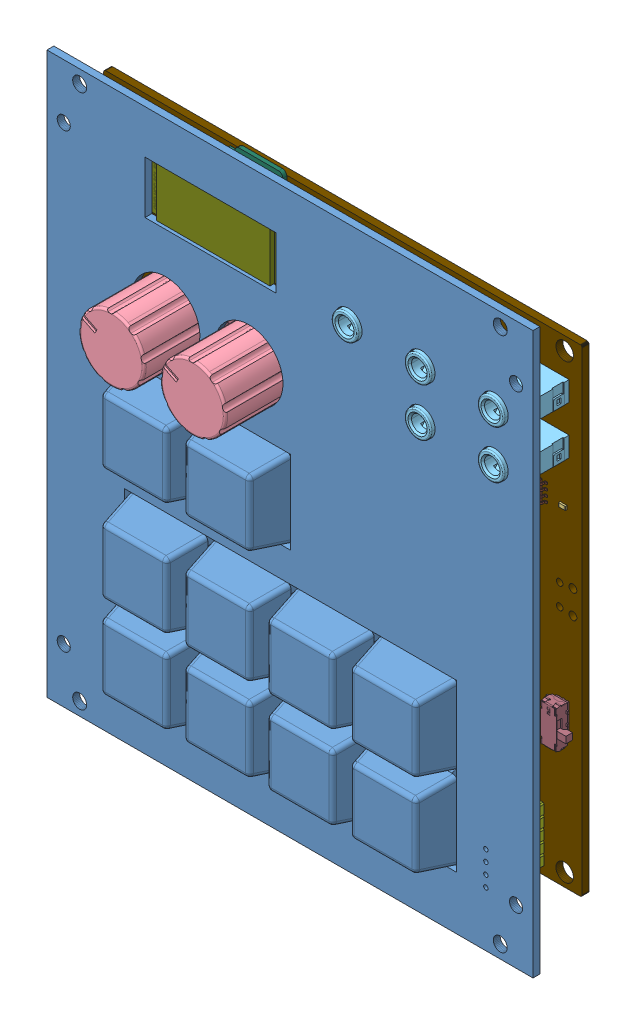
SolidWorks assembly dc31-final, configuration Default. Lengths in mm.
Overall size (111.4 128.5 35.79).
126 component instances, 19 part files, 3 mates.
Components (placement in the parent):
- dc31.step-2: dc31.step [Default] at origin size (109.67 111.23 35.79)
  - MX_WithFlatCap.step-1: MX_WithFlatCap.step [Default] at (131.06 -111.73 7.63) x (-1 0 0) z (0 1 0) size (18 22.4 18)
    - COMPOUND.step-1: COMPOUND.step [Default] at origin size (18 22.4 18)
  - D_SOD-323.step-1: D_SOD-323.step [Default] at (123.7875 -60.54 1.63) x (-1 0 0) z (0 0 1) size (2.5 1.25 1.1)
    - SOLID.step-1: SOLID.step [Default] at origin size (2.5 1.25 1.1)
  - R_0603_1608Metric.step-1: R_0603_1608Metric.step [Default] at (196.19 -44.98 1.63) x (-1 0 0) z (0 0 1) size (1.6 0.8 0.45)
    - SOLID-0.step-1: SOLID-0.step [Default] at origin size (1.6 0.8 0.45)
  - Rotary_Encoder_With_Black_Knob.step-1: Rotary_Encoder_With_Black_Knob.step [Default] at (149.46 -76.86 2.13) size (15.12 15.21 30.51)
    - COMPOUND-1.step-1: COMPOUND-1.step [Default] at origin size (15.12 15.21 30.51)
  - R_0603_1608Metric.step-2: R_0603_1608Metric.step [Default] at (109.45 -92.99 1.63) size (1.6 0.8 0.45)
    - SOLID-0.step-1: SOLID-0.step [Default] at origin size (1.6 0.8 0.45)
  - STX-3790-5N_rA5.step-1: STX-3790-5N_rA5.step [Default] at (182.33 -64.52 12.13) size (9.3 6 15.5)
    - SOLID-2.step-1: SOLID-2.step [Default] at origin size (9.3 6 15.5)
  - C_0805_2012Metric.step-1: C_0805_2012Metric.step [Default] at (101.59 -90.75 1.63) size (2 1.25 1.25)
    - SOLID-3.step-1: SOLID-3.step [Default] at origin size (2 1.25 1.25)
  - D_SOD-323.step-2: D_SOD-323.step [Default] at (142.7375 -108.38 1.63) x (-1 0 0) z (0 0 1) size (2.5 1.25 1.1)
    - SOLID.step-1: SOLID.step [Default] at origin size (2.5 1.25 1.1)
  - PinHeader_1x05_P2.54mm_Vertical.step-1: PinHeader_1x05_P2.54mm_Vertical.step [Default] at (197.07 -137.1396 1.63) size (2.54 12.7 11.54)
    - SOLID-4.step-1: SOLID-4.step [Default] at origin size (2.54 12.7 11.54)
  - D_SOD-323.step-3: D_SOD-323.step [Default] at (111.02 -100.41 1.63) x (-1 0 0) z (0 0 1) size (2.5 1.25 1.1)
    - SOLID.step-1: SOLID.step [Default] at origin size (2.5 1.25 1.1)
  - MX_WithFlatCap.step-2: MX_WithFlatCap.step [Default] at (188.21 -130.78 7.63) x (-1 0 0) z (0 1 0) size (18 22.4 18)
    - COMPOUND.step-1: COMPOUND.step [Default] at origin size (18 22.4 18)
  - D_SOD-323.step-4: D_SOD-323.step [Default] at (180.8375 -108.38 1.63) x (-1 0 0) z (0 0 1) size (2.5 1.25 1.1)
    - SOLID.step-1: SOLID.step [Default] at origin size (2.5 1.25 1.1)
  - SO-5_4.4x3.6mm_P1.27mm.step-1: SO-5_4.4x3.6mm_P1.27mm.step [Default] at (164.72 -44.32 1.63) x (-1 0 0) z (0 0 1) size (6.3 3.6 1.1)
    - SOLID-5.step-1: SOLID-5.step [Default] at origin size (6.3 3.6 1.1)
  - C_0603_1608Metric.step-1: C_0603_1608Metric.step [Default] at (158.57 -44.42 1.63) x (0 1 0) z (0 0 1) size (1.6 0.8 0.8)
    - SOLID-6.step-1: SOLID-6.step [Default] at origin size (1.6 0.8 0.8)
  - R_0603_1608Metric.step-3: R_0603_1608Metric.step [Default] at (164.66 -58.57 1.63) size (1.6 0.8 0.45)
    - SOLID-0.step-1: SOLID-0.step [Default] at origin size (1.6 0.8 0.45)
  - R_0603_1608Metric.step-4: R_0603_1608Metric.step [Default] at (196.15 -69.98 1.63) x (-1 0 0) z (0 0 1) size (1.6 0.8 0.45)
    - SOLID-0.step-1: SOLID-0.step [Default] at origin size (1.6 0.8 0.45)
  - SOT-23.step-1: SOT-23.step [Default] at (182.92 -72.29 1.63) x (0 -1 0) z (0 0 1) size (2.5 3 1.2)
    - SOLID-7.step-1: SOLID-7.step [Default] at origin size (2.5 3 1.2)
  - R_0603_1608Metric.step-5: R_0603_1608Metric.step [Default] at (202.825 -74.605 1.63) x (-1 0 0) z (0 0 1) size (1.6 0.8 0.45)
    - SOLID-0.step-1: SOLID-0.step [Default] at origin size (1.6 0.8 0.45)
  - SOIC-8_3.9x4.9mm_P1.27mm.step-1: SOIC-8_3.9x4.9mm_P1.27mm.step [Default] at (196.135 -73.955 1.63) size (6 4.9 1.75)
    - SOLID-8.step-1: SOLID-8.step [Default] at origin size (6 4.9 1.75)
  - MX_WithFlatCap.step-3: MX_WithFlatCap.step [Default] at (169.16 -130.78 7.63) x (-1 0 0) z (0 1 0) size (18 22.4 18)
    - COMPOUND.step-1: COMPOUND.step [Default] at origin size (18 22.4 18)
  - D_SOD-323.step-5: D_SOD-323.step [Default] at (123.6875 -148.88 1.63) x (-1 0 0) z (0 0 1) size (2.5 1.25 1.1)
    - SOLID.step-1: SOLID.step [Default] at origin size (2.5 1.25 1.1)
  - MX_WithFlatCap.step-4: MX_WithFlatCap.step [Default] at (169.16 -111.73 7.63) x (-1 0 0) z (0 1 0) size (18 22.4 18)
    - COMPOUND.step-1: COMPOUND.step [Default] at origin size (18 22.4 18)
  - L_Wuerth_MAPI-3015.step-1: L_Wuerth_MAPI-3015.step [Default] at (109.97 -96.98 1.63) x (0 -1 0) z (0 0 1) size (3 3 1.5)
    - SOLID-9.step-1: SOLID-9.step [Default] at origin size (3 3 1.5)
  - D_SOD-323.step-6: D_SOD-323.step [Default] at (142.76 -82.54 1.63) x (-1 0 0) z (0 0 1) size (2.5 1.25 1.1)
    - SOLID.step-1: SOLID.step [Default] at origin size (2.5 1.25 1.1)
  - STX-3790-5N_rA5.step-2: STX-3790-5N_rA5.step [Default] at (199.0641 -64.53 12.13) size (9.3 6 15.5)
    - SOLID-2.step-1: SOLID-2.step [Default] at origin size (9.3 6 15.5)
  - MX_WithFlatCap.step-5: MX_WithFlatCap.step [Default] at (150.11 -111.73 7.63) x (-1 0 0) z (0 1 0) size (18 22.4 18)
    - COMPOUND.step-1: COMPOUND.step [Default] at origin size (18 22.4 18)
  - STX-3790-5N_rA5.step-3: STX-3790-5N_rA5.step [Default] at (165.5759 -53.51 12.13) size (9.3 6 15.5)
    - SOLID-2.step-1: SOLID-2.step [Default] at origin size (9.3 6 15.5)
  - D_SOD-323.step-7: D_SOD-323.step [Default] at (195.24 -113.19 1.63) x (0 -1 0) z (0 0 1) size (2.5 1.25 1.1)
    - SOLID.step-1: SOLID.step [Default] at origin size (2.5 1.25 1.1)
  - C_0603_1608Metric.step-2: C_0603_1608Metric.step [Default] at (166.405 -74.59 1.63) x (-1 0 0) z (0 0 1) size (1.6 0.8 0.8)
    - SOLID-6.step-1: SOLID-6.step [Default] at origin size (1.6 0.8 0.8)
  - R_0603_1608Metric.step-6: R_0603_1608Metric.step [Default] at (166.405 -72.55 1.63) size (1.6 0.8 0.45)
    - SOLID-0.step-1: SOLID-0.step [Default] at origin size (1.6 0.8 0.45)
  - R_0603_1608Metric.step-7: R_0603_1608Metric.step [Default] at (190.16 -75.585 1.63) x (-1 0 0) z (0 0 1) size (1.6 0.8 0.45)
    - SOLID-0.step-1: SOLID-0.step [Default] at origin size (1.6 0.8 0.45)
  - R_0603_1608Metric.step-8: R_0603_1608Metric.step [Default] at (190.17 -71.995 1.63) size (1.6 0.8 0.45)
    - SOLID-0.step-1: SOLID-0.step [Default] at origin size (1.6 0.8 0.45)
  - R_0603_1608Metric.step-9: R_0603_1608Metric.step [Default] at (179.81 -44.98 1.63) size (1.6 0.8 0.45)
    - SOLID-0.step-1: SOLID-0.step [Default] at origin size (1.6 0.8 0.45)
  - MX_WithFlatCap.step-6: MX_WithFlatCap.step [Default] at (131.06 -130.78 7.63) x (-1 0 0) z (0 1 0) size (18 22.4 18)
    - COMPOUND.step-1: COMPOUND.step [Default] at origin size (18 22.4 18)
  - MX_WithFlatCap.step-7: MX_WithFlatCap.step [Default] at (131.06 -85.89 7.63) x (-1 0 0) z (0 1 0) size (18 22.4 18)
    - COMPOUND.step-1: COMPOUND.step [Default] at origin size (18 22.4 18)
  - D_SOD-323.step-8: D_SOD-323.step [Default] at (180.8375 -148.88 1.63) x (-1 0 0) z (0 0 1) size (2.5 1.25 1.1)
    - SOLID.step-1: SOLID.step [Default] at origin size (2.5 1.25 1.1)
  - STX-3790-5N_rA5.step-4: STX-3790-5N_rA5.step [Default] at (182.32 -53.51 12.13) size (9.3 6 15.5)
    - SOLID-2.step-1: SOLID-2.step [Default] at origin size (9.3 6 15.5)
  - JS102011SAQN.step-1: JS102011SAQN.step [Default] at (202.735 -116.77 1.83) x (0 1 0) z (1 0 0) size (9 4.3 7.5)
    - SOLID-10.step-1: SOLID-10.step [Default] at origin size (9 4.3 7.5)
  - D_SOD-323.step-9: D_SOD-323.step [Default] at (191.84 -44.98 1.63) size (2.5 1.25 1.1)
    - SOLID.step-1: SOLID.step [Default] at origin size (2.5 1.25 1.1)
  - D_SOD-323.step-10: D_SOD-323.step [Default] at (161.7875 -148.88 1.63) x (-1 0 0) z (0 0 1) size (2.5 1.25 1.1)
    - SOLID.step-1: SOLID.step [Default] at origin size (2.5 1.25 1.1)
  - Rotary_Encoder_With_Black_Knob.step-2: Rotary_Encoder_With_Black_Knob.step [Default] at (130.41 -76.86 1.73) size (15.12 15.21 30.51)
    - COMPOUND-1.step-1: COMPOUND-1.step [Default] at origin size (15.12 15.21 30.51)
  - R_0603_1608Metric.step-10: R_0603_1608Metric.step [Default] at (177.77 -74.02 1.63) x (0 -1 0) z (0 0 1) size (1.6 0.8 0.45)
    - SOLID-0.step-1: SOLID-0.step [Default] at origin size (1.6 0.8 0.45)
  - D_SOD-323.step-11: D_SOD-323.step [Default] at (123.6875 -108.38 1.63) x (-1 0 0) z (0 0 1) size (2.5 1.25 1.1)
    - SOLID.step-1: SOLID.step [Default] at origin size (2.5 1.25 1.1)
  - D_SOD-323.step-12: D_SOD-323.step [Default] at (184.18 -44.98 1.63) size (2.5 1.25 1.1)
    - SOLID.step-1: SOLID.step [Default] at origin size (2.5 1.25 1.1)
  - TSSOP-14_4.4x5mm_P0.65mm.step-1: TSSOP-14_4.4x5mm_P0.65mm.step [Default] at (172.3625 -73.37 1.63) x (-1 0 0) z (0 0 1) size (6.4 5 1)
    - SOLID-11.step-1: SOLID-11.step [Default] at origin size (6.4 5 1)
  - D_SOD-323.step-13: D_SOD-323.step [Default] at (123.69 -82.53 1.63) x (-1 0 0) z (0 0 1) size (2.5 1.25 1.1)
    - SOLID.step-1: SOLID.step [Default] at origin size (2.5 1.25 1.1)
  - MX_WithFlatCap.step-8: MX_WithFlatCap.step [Default] at (188.21 -111.73 7.63) x (-1 0 0) z (0 1 0) size (18 22.4 18)
    - COMPOUND.step-1: COMPOUND.step [Default] at origin size (18 22.4 18)
  - MicroSD.step-1: MicroSD.step [Default] at (133.74 -48.67 1.63) x (-1 0 0) z (0 1 0) size (14.7 2.45 16.8)
    - SOLID-12.step-1: SOLID-12.step [Default] at origin size (14.7 2.45 16.8)
  - OLED 128x32 Display.step-1: OLED 128x32 Display.step [Default] at (113.98 -53.38 10.63) size (38 12 11.2)
    - COMPOUND-13.step-1: COMPOUND-13.step [Default] at origin size (38 12 11.2)
  - C_0805_2012Metric.step-2: C_0805_2012Metric.step [Default] at (100 -96.11 1.63) x (0 -1 0) z (0 0 1) size (2 1.25 1.25)
    - SOLID-3.step-1: SOLID-3.step [Default] at origin size (2 1.25 1.25)
  - D_SOD-323.step-14: D_SOD-323.step [Default] at (142.7375 -148.88 1.63) x (-1 0 0) z (0 0 1) size (2.5 1.25 1.1)
    - SOLID.step-1: SOLID.step [Default] at origin size (2.5 1.25 1.1)
  - STX-3790-5N_rA5.step-5: STX-3790-5N_rA5.step [Default] at (199.0641 -53.51 12.13) size (9.3 6 15.5)
    - SOLID-2.step-1: SOLID-2.step [Default] at origin size (9.3 6 15.5)
  - D_SOD-323.step-15: D_SOD-323.step [Default] at (142.72 -60.58 1.63) x (-1 0 0) z (0 0 1) size (2.5 1.25 1.1)
    - SOLID.step-1: SOLID.step [Default] at origin size (2.5 1.25 1.1)
  - D_SOD-323.step-16: D_SOD-323.step [Default] at (161.7875 -108.38 1.63) x (-1 0 0) z (0 0 1) size (2.5 1.25 1.1)
    - SOLID.step-1: SOLID.step [Default] at origin size (2.5 1.25 1.1)
  - C_0805_2012Metric.step-3: C_0805_2012Metric.step [Default] at (105.79 -98.12 1.63) x (-1 0 0) z (0 0 1) size (2 1.25 1.25)
    - SOLID-3.step-1: SOLID-3.step [Default] at origin size (2 1.25 1.25)
  - MX_WithFlatCap.step-9: MX_WithFlatCap.step [Default] at (150.11 -130.78 7.63) x (-1 0 0) z (0 1 0) size (18 22.4 18)
    - COMPOUND.step-1: COMPOUND.step [Default] at origin size (18 22.4 18)
  - C_0603_1608Metric.step-3: C_0603_1608Metric.step [Default] at (133.705 -60.91 1.63) size (1.6 0.8 0.8)
    - SOLID-6.step-1: SOLID-6.step [Default] at origin size (1.6 0.8 0.8)
  - R_0603_1608Metric.step-11: R_0603_1608Metric.step [Default] at (183.77 -75.53 1.63) size (1.6 0.8 0.45)
    - SOLID-0.step-1: SOLID-0.step [Default] at origin size (1.6 0.8 0.45)
  - C_0603_1608Metric.step-4: C_0603_1608Metric.step [Default] at (190.16 -73.765 1.63) x (-1 0 0) z (0 0 1) size (1.6 0.8 0.8)
    - SOLID-6.step-1: SOLID-6.step [Default] at origin size (1.6 0.8 0.8)
  - MX_WithFlatCap.step-10: MX_WithFlatCap.step [Default] at (150.11 -85.89 7.63) x (-1 0 0) z (0 1 0) size (18 22.4 18)
    - COMPOUND.step-1: COMPOUND.step [Default] at origin size (18 22.4 18)
  - IDC-Header_2x05_P2.54mm_Vertical.step-1: IDC-Header_2x05_P2.54mm_Vertical.step [Default] at (105.5878 -117.7036 -0.05) x (-1 0 0) z (0 0 -1) size (9.1 20.36 12.1)
    - SOLID-14.step-1: SOLID-14.step [Default] at origin size (9.1 20.36 12.1)
  - dc31 PCB.step-1: dc31 PCB.step [Default] at origin size (109.67 109.49 1.58)
- dc31-front2.step-1: dc31-front2.step [Default] at (-0.0214 0.019 12.13) size (111.4 128.5 1.58)
  - dc31-front PCB.step-1: dc31-front PCB.step [Default] at origin size (111.4 128.5 1.58)
Mates (geometry in assembly coordinates):
- Coincident4: coincident: plane of dc31.step-2/STX-3790-5N_rA5.step-2/SOLID-2.step-1 through (194.8641 -64.53 12.13) normal (0 0 1); plane of dc31-front2.step-1/dc31-front PCB.step-1 through (152.15 -95.6 12.13) normal (0 0 -1)
- Width1: width: plane of dc31-front2.step-1/dc31-front PCB.step-1 through (207.85 -31.35 12.13) normal (1 0 0); plane of dc31.step-2/dc31 PCB.step-1 through (96.45 -159.85 12.13) normal (-1 0 0); plane of dc31-front2.step-1/dc31-front PCB.step-1 through (97.3136 -149.8464 0) normal (-1 0 0); plane of dc31.step-2/dc31 PCB.step-1 through (206.9864 -41.3536 0) normal (1 0 0)
- Width2: width anti-aligned: plane of dc31-front2.step-1/dc31-front PCB.step-1 through (96.45 -31.35 12.13) normal (0 1 0); plane of dc31.step-2/dc31 PCB.step-1 through (207.85 -159.85 12.13) normal (0 -1 0); plane of dc31-front2.step-1/dc31-front PCB.step-1 through (206.4864 -150.3464 0) normal (0 -1 0); plane of dc31.step-2/dc31 PCB.step-1 through (97.8136 -40.8536 0) normal (0 1 0)
